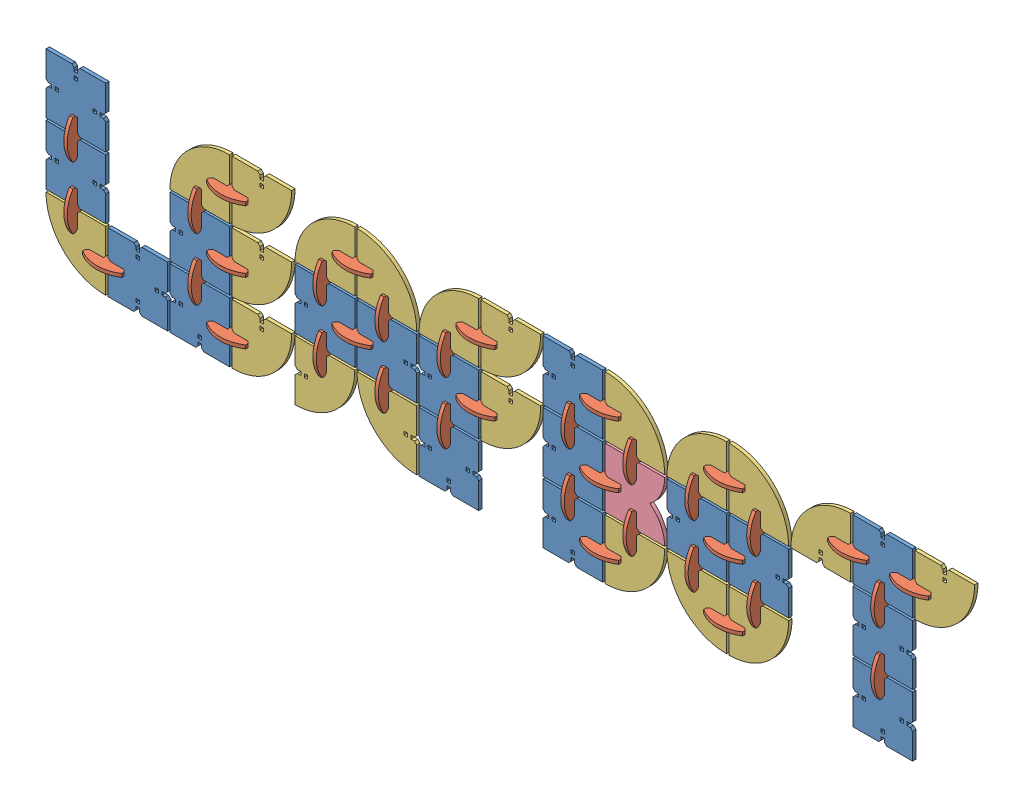
SolidWorks assembly Assem1, configuration Default. Lengths in mm.
Overall size (809 160 21).
74 component instances, 4 part files, 220 mates.
Components (placement in the parent):
- Part4-1: Part4 [Default] at (2.3941 27.4679 47.1684) size (52 52 3)
- Part6-1: Part6 [Default] at (-24.6059 25.9679 48.6684) x (1 0 0) z (0 1 0) size (34 21 3)
- Part4-2: Part4 [Default] at (-51.6059 81.4679 47.1684) size (52 52 3)
- Part5-1: Part5 [Default] at (-51.6059 27.4679 47.1684) x (-1 0 0) z (0 0 1) size (52 52 3)
- Part6-2: Part6 [Default] at (-53.1059 54.4679 48.6684) x (0 -1 0) z (1 0 0) size (34 21 3)
- Part6-3: Part6 [Default] at (-53.1059 108.4679 48.6684) x (0 1 0) z (1 0 0) size (34 21 3)
- Part4-3: Part4 [Default] at (-51.6059 135.4679 47.1684) size (52 52 3)
- Part4-4: Part4 [Default] at (56.3941 27.4679 47.1684) size (52 52 3)
- Part4-5: Part4 [Default] at (56.3941 81.4679 47.1684) size (52 52 3)
- Part6-4: Part6 [Default] at (57.8941 54.4679 48.6684) x (0 -1 0) z (-1 0 0) size (34 21 3)
- Part6-5: Part6 [Default] at (54.8941 108.4679 48.6684) x (0 1 0) z (1 0 0) size (34 21 3)
- Part5-2: Part5 [Default] at (56.3941 135.4679 47.1684) x (0 1 0) z (0 0 1) size (52 52 3)
- Part6-6: Part6 [Default] at (83.3941 28.9679 48.6684) x (1 0 0) z (0 -1 0) size (34 21 3)
- Part6-7: Part6 [Default] at (83.3941 82.9679 48.6684) x (1 0 0) z (0 -1 0) size (34 21 3)
- Part6-8: Part6 [Default] at (83.3941 136.9679 48.6684) x (1 0 0) z (0 -1 0) size (34 21 3)
- Part5-3: Part5 [Default] at (110.3941 135.4679 47.1684) x (0 -1 0) z (0 0 1) size (52 52 3)
- Part5-4: Part5 [Default] at (110.3941 81.4679 47.1684) x (0 -1 0) z (0 0 1) size (52 52 3)
- Part5-5: Part5 [Default] at (110.3941 27.4679 47.1684) x (0 -1 0) z (0 0 1) size (52 52 3)
- Part5-6: Part5 [Default] at (165.3941 27.4679 47.1684) x (0 -1 0) z (0 0 1) size (52 52 3)
- Part4-6: Part4 [Default] at (165.3941 81.4679 47.1684) size (52 52 3)
- Part6-9: Part6 [Default] at (163.8941 54.4679 48.6684) x (0 1 0) z (1 0 0) size (34 21 3)
- Part5-7: Part5 [Default] at (165.3941 135.4679 47.1684) x (0 1 0) z (0 0 1) size (52 52 3)
- Part6-10: Part6 [Default] at (163.8941 108.4679 48.6684) x (0 1 0) z (1 0 0) size (34 21 3)
- Part6-11: Part6 [Default] at (192.3941 136.9679 48.6684) x (1 0 0) z (0 -1 0) size (34 21 3)
- Part5-8: Part5 [Default] at (219.3941 135.4679 47.1684) size (52 52 3)
- Part6-12: Part6 [Default] at (220.8941 108.4679 48.6684) x (0 1 0) z (-1 0 0) size (34 21 3)
- Part4-7: Part4 [Default] at (219.3941 81.4679 47.1684) size (52 52 3)
- Part6-13: Part6 [Default] at (192.3941 82.9679 48.6684) x (1 0 0) z (0 -1 0) size (34 21 3)
- Part6-14: Part6 [Default] at (220.8941 54.4679 48.6684) x (0 1 0) z (-1 0 0) size (34 21 3)
- Part5-9: Part5 [Default] at (219.3941 27.4679 47.1684) x (-1 0 0) z (0 0 1) size (52 52 3)
- Part4-8: Part4 [Default] at (273.3941 27.4679 47.1684) size (52 52 3)
- Part6-15: Part6 [Default] at (271.8941 54.4679 48.6684) x (0 -1 0) z (1 0 0) size (34 21 3)
- Part4-9: Part4 [Default] at (273.3941 81.4679 47.1684) size (52 52 3)
- Part6-16: Part6 [Default] at (271.8941 108.4679 48.6684) x (0 1 0) z (1 0 0) size (34 21 3)
- Part5-10: Part5 [Default] at (273.3941 135.4679 47.1684) x (0 1 0) z (0 0 1) size (52 52 3)
- Part6-17: Part6 [Default] at (300.3941 82.9679 48.6684) x (1 0 0) z (0 -1 0) size (34 21 3)
- Part6-18: Part6 [Default] at (300.3941 136.9679 48.6684) x (1 0 0) z (0 -1 0) size (34 21 3)
- Part5-11: Part5 [Default] at (327.3941 135.4679 47.1684) x (0 -1 0) z (0 0 1) size (52 52 3)
- Part5-12: Part5 [Default] at (327.3941 81.4679 47.1684) x (0 -1 0) z (0 0 1) size (52 52 3)
- Part4-10: Part4 [Default] at (381.3941 27.4679 47.1684) size (52 52 3)
- Part6-19: Part6 [Default] at (379.8941 54.4679 48.6684) x (0 1 0) z (1 0 0) size (34 21 3)
- Part4-11: Part4 [Default] at (381.3941 81.4679 47.1684) size (52 52 3)
- Part4-12: Part4 [Default] at (381.3941 135.4679 47.1684) size (52 52 3)
- Part6-20: Part6 [Default] at (379.8941 108.4679 48.6684) x (0 1 0) z (1 0 0) size (34 21 3)
- Part6-21: Part6 [Default] at (408.3941 28.9679 48.6684) x (1 0 0) z (0 -1 0) size (34 21 3)
- Part6-22: Part6 [Default] at (408.3941 79.9679 48.6684) x (1 0 0) z (0 1 0) size (34 21 3)
- Part6-23: Part6 [Default] at (408.3941 133.9679 48.6684) x (1 0 0) z (0 1 0) size (34 21 3)
- Part5-13: Part5 [Default] at (435.3941 135.4679 47.1684) size (52 52 3)
- Part7-1: Part7 [Default] at (435.3941 81.4679 47.1684) size (52 52 3)
- Part5-14: Part5 [Default] at (435.3941 27.4679 47.1684) x (0 -1 0) z (0 0 1) size (52 52 3)
- Part6-24: Part6 [Default] at (436.8941 108.4679 48.6684) x (0 -1 0) z (-1 0 0) size (34 21 3)
- Part6-25: Part6 [Default] at (436.8941 54.4679 48.6684) x (0 -1 0) z (-1 0 0) size (34 21 3)
- Part5-15: Part5 [Default] at (489.3941 27.4679 47.1684) x (-1 0 0) z (0 0 1) size (52 52 3)
- Part6-26: Part6 [Default] at (490.8941 54.4679 48.6684) x (0 -1 0) z (-1 0 0) size (34 21 3)
- Part4-13: Part4 [Default] at (489.3941 81.4679 47.1684) size (52 52 3)
- Part6-27: Part6 [Default] at (490.8941 108.4679 48.6684) x (0 -1 0) z (-1 0 0) size (34 21 3)
- Part5-16: Part5 [Default] at (489.3941 135.4679 47.1684) x (0 1 0) z (0 0 1) size (52 52 3)
- Part6-28: Part6 [Default] at (516.3941 136.9679 48.6684) x (1 0 0) z (0 -1 0) size (34 21 3)
- Part6-29: Part6 [Default] at (516.3941 82.9679 48.6684) x (1 0 0) z (0 -1 0) size (34 21 3)
- Part6-30: Part6 [Default] at (516.3941 25.9679 48.6684) x (1 0 0) z (0 1 0) size (34 21 3)
- Part5-17: Part5 [Default] at (543.3941 135.4679 47.1684) size (52 52 3)
- Part4-14: Part4 [Default] at (543.3941 81.4679 47.1684) size (52 52 3)
- Part5-18: Part5 [Default] at (543.3941 27.4679 47.1684) x (0 -1 0) z (0 0 1) size (52 52 3)
- Part6-31: Part6 [Default] at (544.8941 108.4679 48.6684) x (0 -1 0) z (-1 0 0) size (34 21 3)
- Part6-32: Part6 [Default] at (544.8941 54.4679 48.6684) x (0 -1 0) z (-1 0 0) size (34 21 3)
- Part5-19: Part5 [Default] at (597.3941 135.4679 47.1684) x (0 1 0) z (0 0 1) size (52 52 3)
- Part6-33: Part6 [Default] at (624.3941 136.9679 48.6684) x (1 0 0) z (0 -1 0) size (34 21 3)
- Part4-15: Part4 [Default] at (651.3941 135.4679 47.1684) size (52 52 3)
- Part4-16: Part4 [Default] at (651.3941 81.4679 47.1684) size (52 52 3)
- Part4-17: Part4 [Default] at (651.3941 27.4679 47.1684) size (52 52 3)
- Part6-34: Part6 [Default] at (678.3941 136.9679 48.6684) x (1 0 0) z (0 -1 0) size (34 21 3)
- Part5-20: Part5 [Default] at (705.3941 135.4679 50.1684) x (1 0 0) z (0 0 -1) size (52 52 3)
- Part6-35: Part6 [Default] at (652.8941 108.4679 48.6684) x (0 -1 0) z (-1 0 0) size (34 21 3)
- Part6-36: Part6 [Default] at (652.8941 54.4679 48.6684) x (0 -1 0) z (-1 0 0) size (34 21 3)
Mates (geometry in assembly coordinates):
- Coincident5: coincident anti-aligned: plane of Part4-1 through (-21.6059 28.9679 50.1684) normal (0 -1 0); plane of Part6-1 through (-24.6059 28.9679 69.5684) normal (0 1 0)
- Coincident6: coincident anti-aligned: plane of Part4-1 through (2.3941 27.4679 47.1684) normal (0 0 -1); plane of Part6-1 through (-15.6059 28.9679 47.1684) normal (0 0 1)
- Coincident7: coincident anti-aligned: plane of Part4-1 through (-18.6059 27.4679 50.1684) normal (-1 0 0); plane of Part6-1 through (-18.6059 28.9679 47.1684) normal (1 0 0)
- Coincident8: coincident anti-aligned: plane of Part6-1 through (-24.6059 25.9679 69.5684) normal (0 -1 0); plane of Part5-1 through (-27.6059 25.9679 50.1684) normal (0 1 0)
- Coincident9: coincident aligned: plane of Part4-1 through (2.3941 27.4679 50.1684) normal (0 0 1); plane of Part5-1 through (-25.6059 53.4679 50.1684) normal (0 0 1)
- Coincident10: coincident anti-aligned: plane of Part6-1 through (-30.6059 28.9679 50.1684) normal (-1 0 0); plane of Part5-1 through (-30.6059 25.9679 50.1684) normal (1 0 0)
- Coincident12: coincident anti-aligned: plane of Part5-1 through (-50.1059 48.4679 50.1684) normal (0 1 0); plane of Part6-2 through (-50.1059 48.4679 47.1684) normal (0 -1 0)
- Coincident13: coincident anti-aligned: plane of Part5-1 through (-50.1059 51.4679 50.1684) normal (-1 0 0); plane of Part6-2 through (-50.1059 54.4679 69.5684) normal (1 0 0)
- Coincident14: coincident anti-aligned: plane of Part5-1 through (-25.6059 53.4679 47.1684) normal (0 0 -1); plane of Part6-2 through (-50.1059 45.4679 47.1684) normal (0 0 1)
- Coincident15: coincident anti-aligned: plane of Part4-2 through (-51.6059 60.4679 50.1684) normal (0 -1 0); plane of Part6-2 through (-50.1059 60.4679 50.1684) normal (0 1 0)
- Coincident16: coincident: plane of Part4-2 through (-51.6059 81.4679 47.1684) normal (0 0 -1); line of Part6-2 through (-50.1059 66.4679 47.1684) axis (0 1 0)
- Coincident17: coincident anti-aligned: plane of Part4-2 through (-53.1059 63.4679 50.1684) normal (1 0 0); plane of Part6-2 through (-53.1059 54.4679 69.5684) normal (-1 0 0)
- Coincident18: coincident anti-aligned: plane of Part4-2 through (-50.1059 105.4679 50.1684) normal (-1 0 0); plane of Part6-3 through (-50.1059 108.4679 27.7684) normal (1 0 0)
- Coincident19: coincident anti-aligned: plane of Part4-2 through (-51.6059 102.4679 50.1684) normal (0 1 0); plane of Part6-3 through (-50.1059 102.4679 47.1684) normal (0 -1 0)
- Coincident20: coincident anti-aligned: plane of Part4-2 through (-51.6059 81.4679 47.1684) normal (0 0 -1); plane of Part6-3 through (-50.1059 99.4679 47.1684) normal (0 0 1)
- Coincident21: coincident anti-aligned: plane of Part6-3 through (-50.1059 123.4679 50.1684) normal (0 0 -1); plane of Part4-3 through (-51.6059 135.4679 50.1684) normal (0 0 1)
- Coincident22: coincident anti-aligned: plane of Part6-3 through (-53.1059 108.4679 27.7684) normal (-1 0 0); plane of Part4-3 through (-53.1059 111.4679 50.1684) normal (1 0 0)
- Coincident23: coincident anti-aligned: plane of Part6-3 through (-50.1059 114.4679 50.1684) normal (0 1 0); plane of Part4-3 through (-51.6059 114.4679 50.1684) normal (0 -1 0)
- Coincident24: coincident aligned: plane of Part4-1 through (2.3941 27.4679 50.1684) normal (0 0 1); plane of Part4-4 through (56.3941 27.4679 50.1684) normal (0 0 1)
- Coincident25: coincident aligned: plane of Part4-1 through (5.8941 1.4679 50.1684) normal (0 -1 0); plane of Part4-4 through (30.3941 1.4679 50.1684) normal (0 -1 0)
- Distance1: distance = 2 mm anti-aligned: plane of Part4-4 through (30.3941 23.9679 50.1684) normal (-1 0 0); plane of Part4-1 through (28.3941 1.4679 50.1684) normal (1 0 0)
- Coincident27: coincident anti-aligned: plane of Part4-4 through (54.8941 48.4679 50.1684) normal (1 0 0); plane of Part6-4 through (54.8941 54.4679 27.7684) normal (-1 0 0)
- Coincident28: coincident anti-aligned: plane of Part4-4 through (56.3941 48.4679 50.1684) normal (0 1 0); plane of Part6-4 through (54.8941 48.4679 50.1684) normal (0 -1 0)
- Coincident29: coincident anti-aligned: plane of Part4-4 through (56.3941 27.4679 47.1684) normal (0 0 -1); plane of Part6-4 through (54.8941 45.4679 47.1684) normal (0 0 1)
- Coincident30: coincident anti-aligned: plane of Part4-5 through (56.3941 60.4679 50.1684) normal (0 -1 0); plane of Part6-4 through (54.8941 60.4679 47.1684) normal (0 1 0)
- Coincident31: coincident: plane of Part4-5 through (56.3941 81.4679 50.1684) normal (0 0 1); line of Part6-4 through (57.8941 66.4679 50.1684) axis (0 1 0)
- Coincident32: coincident anti-aligned: plane of Part4-5 through (57.8941 60.4679 50.1684) normal (-1 0 0); plane of Part6-4 through (57.8941 54.4679 27.7684) normal (1 0 0)
- Coincident33: coincident anti-aligned: plane of Part4-5 through (57.8941 105.4679 50.1684) normal (-1 0 0); plane of Part6-5 through (57.8941 108.4679 27.7684) normal (1 0 0)
- Coincident34: coincident anti-aligned: plane of Part4-5 through (56.3941 102.4679 50.1684) normal (0 1 0); plane of Part6-5 through (57.8941 102.4679 47.1684) normal (0 -1 0)
- Coincident35: coincident anti-aligned: plane of Part4-5 through (56.3941 81.4679 47.1684) normal (0 0 -1); plane of Part6-5 through (57.8941 93.4679 47.1684) normal (0 0 1)
- Coincident37: coincident anti-aligned: plane of Part6-5 through (57.8941 114.4679 50.1684) normal (0 1 0); plane of Part5-2 through (54.8941 114.4679 50.1684) normal (0 -1 0)
- Coincident38: coincident anti-aligned: plane of Part6-5 through (57.8941 108.4679 27.7684) normal (1 0 0); plane of Part5-2 through (57.8941 114.4679 50.1684) normal (-1 0 0)
- Coincident39: coincident: line of Part6-5 through (57.8941 120.4679 50.1684) axis (0 1 0); plane of Part5-2 through (82.3941 109.4679 50.1684) normal (0 0 1)
- Coincident40: coincident anti-aligned: plane of Part4-4 through (80.3941 25.9679 50.1684) normal (0 1 0); plane of Part6-6 through (83.3941 25.9679 27.7684) normal (0 -1 0)
- Coincident41: coincident anti-aligned: plane of Part4-4 through (77.3941 27.4679 50.1684) normal (1 0 0); plane of Part6-6 through (77.3941 25.9679 47.1684) normal (-1 0 0)
- Coincident42: coincident anti-aligned: plane of Part4-4 through (56.3941 27.4679 47.1684) normal (0 0 -1); plane of Part6-6 through (74.3941 25.9679 47.1684) normal (0 0 1)
- Coincident43: coincident anti-aligned: plane of Part4-5 through (80.3941 79.9679 50.1684) normal (0 1 0); plane of Part6-7 through (83.3941 79.9679 27.7684) normal (0 -1 0)
- Coincident44: coincident anti-aligned: plane of Part4-5 through (56.3941 81.4679 47.1684) normal (0 0 -1); plane of Part6-7 through (74.3941 79.9679 47.1684) normal (0 0 1)
- Coincident45: coincident anti-aligned: plane of Part4-5 through (77.3941 81.4679 50.1684) normal (1 0 0); plane of Part6-7 through (77.3941 79.9679 47.1684) normal (-1 0 0)
- Coincident46: coincident anti-aligned: plane of Part5-2 through (80.3941 133.9679 50.1684) normal (0 1 0); plane of Part6-8 through (83.3941 133.9679 27.7684) normal (0 -1 0)
- Coincident47: coincident anti-aligned: plane of Part5-2 through (77.3941 133.9679 50.1684) normal (1 0 0); plane of Part6-8 through (77.3941 133.9679 47.1684) normal (-1 0 0)
- Coincident48: coincident anti-aligned: plane of Part5-2 through (82.3941 109.4679 47.1684) normal (0 0 -1); plane of Part6-8 through (68.3941 133.9679 47.1684) normal (0 0 1)
- Coincident49: coincident anti-aligned: plane of Part6-8 through (89.3941 133.9679 50.1684) normal (1 0 0); plane of Part5-3 through (89.3941 136.9679 50.1684) normal (-1 0 0)
- Coincident50: coincident anti-aligned: plane of Part6-8 through (83.3941 133.9679 27.7684) normal (0 -1 0); plane of Part5-3 through (89.3941 133.9679 50.1684) normal (0 1 0)
- Coincident51: coincident anti-aligned: plane of Part6-8 through (92.3941 133.9679 50.1684) normal (0 0 -1); plane of Part5-3 through (84.3941 161.4679 50.1684) normal (0 0 1)
- Coincident52: coincident anti-aligned: plane of Part6-7 through (89.3941 79.9679 50.1684) normal (1 0 0); plane of Part5-4 through (89.3941 82.9679 50.1684) normal (-1 0 0)
- Coincident53: coincident anti-aligned: plane of Part6-7 through (92.3941 79.9679 50.1684) normal (0 0 -1); plane of Part5-4 through (84.3941 107.4679 50.1684) normal (0 0 1)
- Coincident54: coincident anti-aligned: plane of Part6-7 through (83.3941 82.9679 27.7684) normal (0 1 0); plane of Part5-4 through (86.3941 82.9679 50.1684) normal (0 -1 0)
- Coincident55: coincident anti-aligned: plane of Part6-6 through (89.3941 25.9679 50.1684) normal (1 0 0); plane of Part5-5 through (89.3941 28.9679 50.1684) normal (-1 0 0)
- Coincident56: coincident anti-aligned: plane of Part6-6 through (89.3941 25.9679 50.1684) normal (1 0 0); plane of Part5-5 through (89.3941 28.9679 50.1684) normal (-1 0 0)
- Coincident57: coincident anti-aligned: plane of Part6-6 through (98.3941 25.9679 50.1684) normal (0 0 -1); plane of Part5-5 through (84.3941 53.4679 50.1684) normal (0 0 1)
- Coincident58: coincident aligned: plane of Part5-5 through (84.3941 53.4679 50.1684) normal (0 0 1); plane of Part5-6 through (139.3941 53.4679 50.1684) normal (0 0 1)
- Distance2: distance = 165 mm anti-aligned: plane of Part5-6 through (139.3941 53.4679 50.1684) normal (-1 0 0); plane of Part5-1 through (-25.6059 1.4679 50.1684) normal (1 0 0)
- Coincident60: coincident aligned: plane of Part5-5 through (136.3941 53.4679 50.1684) normal (0 1 0); plane of Part5-6 through (191.3941 53.4679 50.1684) normal (0 1 0)
- Coincident61: coincident anti-aligned: plane of Part5-6 through (166.8941 51.4679 50.1684) normal (-1 0 0); plane of Part6-9 through (166.8941 54.4679 27.7684) normal (1 0 0)
- Coincident62: coincident anti-aligned: plane of Part5-6 through (166.8941 48.4679 50.1684) normal (0 1 0); plane of Part6-9 through (166.8941 48.4679 47.1684) normal (0 -1 0)
- Coincident63: coincident anti-aligned: plane of Part5-6 through (139.3941 53.4679 47.1684) normal (0 0 -1); plane of Part6-9 through (166.8941 45.4679 47.1684) normal (0 0 1)
- Coincident64: coincident anti-aligned: plane of Part4-6 through (165.3941 81.4679 50.1684) normal (0 0 1); plane of Part6-9 through (166.8941 63.4679 50.1684) normal (0 0 -1)
- Coincident66: coincident anti-aligned: plane of Part4-6 through (165.3941 60.4679 50.1684) normal (0 -1 0); plane of Part6-9 through (166.8941 60.4679 50.1684) normal (0 1 0)
- Coincident67: coincident anti-aligned: plane of Part4-6 through (166.8941 66.4679 50.1684) normal (-1 0 0); plane of Part6-9 through (166.8941 54.4679 27.7684) normal (1 0 0)
- Coincident69: coincident anti-aligned: plane of Part6-6 through (83.3941 28.9679 27.7684) normal (0 1 0); plane of Part5-5 through (86.3941 28.9679 50.1684) normal (0 -1 0)
- Coincident70: coincident anti-aligned: plane of Part4-6 through (166.8941 105.4679 50.1684) normal (-1 0 0); plane of Part6-10 through (166.8941 108.4679 27.7684) normal (1 0 0)
- Coincident71: coincident anti-aligned: plane of Part4-6 through (165.3941 102.4679 50.1684) normal (0 1 0); plane of Part6-10 through (166.8941 102.4679 47.1684) normal (0 -1 0)
- Coincident72: coincident anti-aligned: plane of Part4-6 through (165.3941 81.4679 50.1684) normal (0 0 1); plane of Part6-10 through (166.8941 99.4679 50.1684) normal (0 0 -1)
- Coincident73: coincident anti-aligned: plane of Part5-7 through (191.3941 109.4679 50.1684) normal (0 0 1); plane of Part6-10 through (166.8941 117.4679 50.1684) normal (0 0 -1)
- Coincident74: coincident anti-aligned: plane of Part5-7 through (163.8941 114.4679 50.1684) normal (0 -1 0); plane of Part6-10 through (166.8941 114.4679 50.1684) normal (0 1 0)
- Coincident75: coincident anti-aligned: plane of Part5-7 through (163.8941 111.4679 50.1684) normal (1 0 0); plane of Part6-10 through (163.8941 108.4679 27.7684) normal (-1 0 0)
- Coincident76: coincident anti-aligned: plane of Part5-7 through (189.3941 133.9679 50.1684) normal (0 1 0); plane of Part6-11 through (192.3941 133.9679 27.7684) normal (0 -1 0)
- Coincident77: coincident anti-aligned: plane of Part5-7 through (186.3941 133.9679 50.1684) normal (1 0 0); plane of Part6-11 through (186.3941 133.9679 47.1684) normal (-1 0 0)
- Coincident78: coincident anti-aligned: plane of Part5-7 through (191.3941 109.4679 47.1684) normal (0 0 -1); plane of Part6-11 through (183.3941 133.9679 47.1684) normal (0 0 1)
- Coincident79: coincident anti-aligned: plane of Part6-11 through (207.3941 133.9679 50.1684) normal (0 0 -1); plane of Part5-8 through (193.3941 109.4679 50.1684) normal (0 0 1)
- Coincident80: coincident anti-aligned: plane of Part6-11 through (198.3941 133.9679 50.1684) normal (1 0 0); plane of Part5-8 through (198.3941 136.9679 50.1684) normal (-1 0 0)
- Coincident81: coincident anti-aligned: plane of Part6-11 through (192.3941 136.9679 27.7684) normal (0 1 0); plane of Part5-8 through (195.3941 136.9679 50.1684) normal (0 -1 0)
- Coincident82: coincident anti-aligned: plane of Part5-8 through (217.8941 111.4679 50.1684) normal (1 0 0); plane of Part6-12 through (217.8941 108.4679 69.5684) normal (-1 0 0)
- Coincident83: coincident anti-aligned: plane of Part5-8 through (217.8941 114.4679 50.1684) normal (0 -1 0); plane of Part6-12 through (217.8941 114.4679 47.1684) normal (0 1 0)
- Coincident84: coincident anti-aligned: plane of Part5-8 through (193.3941 109.4679 47.1684) normal (0 0 -1); plane of Part6-12 through (217.8941 117.4679 47.1684) normal (0 0 1)
- Coincident85: coincident anti-aligned: plane of Part6-12 through (217.8941 102.4679 50.1684) normal (0 -1 0); plane of Part4-7 through (219.3941 102.4679 50.1684) normal (0 1 0)
- Coincident86: coincident anti-aligned: plane of Part6-12 through (217.8941 99.4679 50.1684) normal (0 0 -1); plane of Part4-7 through (219.3941 81.4679 50.1684) normal (0 0 1)
- Coincident87: coincident anti-aligned: plane of Part6-12 through (217.8941 108.4679 69.5684) normal (-1 0 0); plane of Part4-7 through (217.8941 102.4679 50.1684) normal (1 0 0)
- Coincident88: coincident anti-aligned: plane of Part4-6 through (189.3941 79.9679 50.1684) normal (0 1 0); plane of Part6-13 through (192.3941 79.9679 27.7684) normal (0 -1 0)
- Coincident89: coincident anti-aligned: plane of Part4-6 through (165.3941 81.4679 47.1684) normal (0 0 -1); plane of Part6-13 through (183.3941 79.9679 47.1684) normal (0 0 1)
- Coincident90: coincident anti-aligned: plane of Part4-6 through (186.3941 81.4679 50.1684) normal (1 0 0); plane of Part6-13 through (186.3941 79.9679 47.1684) normal (-1 0 0)
- Coincident91: coincident anti-aligned: plane of Part4-7 through (217.8941 57.4679 50.1684) normal (1 0 0); plane of Part6-14 through (217.8941 54.4679 69.5684) normal (-1 0 0)
- Coincident92: coincident anti-aligned: plane of Part4-7 through (219.3941 60.4679 50.1684) normal (0 -1 0); plane of Part6-14 through (217.8941 60.4679 47.1684) normal (0 1 0)
- Coincident93: coincident anti-aligned: plane of Part4-7 through (219.3941 81.4679 50.1684) normal (0 0 1); plane of Part6-14 through (217.8941 63.4679 50.1684) normal (0 0 -1)
- Coincident94: coincident anti-aligned: plane of Part6-14 through (217.8941 48.4679 50.1684) normal (0 -1 0); plane of Part5-9 through (220.8941 48.4679 50.1684) normal (0 1 0)
- Coincident95: coincident anti-aligned: plane of Part6-14 through (217.8941 45.4679 50.1684) normal (0 0 -1); plane of Part5-9 through (245.3941 53.4679 50.1684) normal (0 0 1)
- Coincident96: coincident anti-aligned: plane of Part6-14 through (217.8941 54.4679 69.5684) normal (-1 0 0); plane of Part5-9 through (217.8941 48.4679 50.1684) normal (1 0 0)
- Coincident97: coincident aligned: plane of Part5-9 through (245.3941 53.4679 50.1684) normal (0 0 1); plane of Part4-8 through (273.3941 27.4679 50.1684) normal (0 0 1)
- Coincident98: coincident aligned: plane of Part4-4 through (59.8941 1.4679 50.1684) normal (0 -1 0); plane of Part4-8 through (247.3941 1.4679 50.1684) normal (0 -1 0)
- Distance3: distance = 2 mm anti-aligned: plane of Part4-8 through (247.3941 23.9679 50.1684) normal (-1 0 0); plane of Part5-9 through (245.3941 1.4679 50.1684) normal (1 0 0)
- Coincident100: coincident anti-aligned: plane of Part4-8 through (273.3941 48.4679 50.1684) normal (0 1 0); plane of Part6-15 through (274.8941 48.4679 47.1684) normal (0 -1 0)
- Coincident101: coincident anti-aligned: plane of Part4-8 through (273.3941 27.4679 50.1684) normal (0 0 1); plane of Part6-15 through (274.8941 45.4679 50.1684) normal (0 0 -1)
- Coincident102: coincident anti-aligned: plane of Part4-8 through (274.8941 51.4679 50.1684) normal (-1 0 0); plane of Part6-15 through (274.8941 54.4679 69.5684) normal (1 0 0)
- Coincident103: coincident anti-aligned: plane of Part6-15 through (274.8941 69.4679 50.1684) normal (0 0 -1); plane of Part4-9 through (273.3941 81.4679 50.1684) normal (0 0 1)
- Coincident104: coincident anti-aligned: plane of Part6-15 through (271.8941 54.4679 69.5684) normal (-1 0 0); plane of Part4-9 through (271.8941 57.4679 50.1684) normal (1 0 0)
- Coincident105: coincident anti-aligned: plane of Part6-15 through (274.8941 60.4679 50.1684) normal (0 1 0); plane of Part4-9 through (273.3941 60.4679 50.1684) normal (0 -1 0)
- Coincident106: coincident anti-aligned: plane of Part4-9 through (274.8941 105.4679 50.1684) normal (-1 0 0); plane of Part6-16 through (274.8941 108.4679 27.7684) normal (1 0 0)
- Coincident107: coincident anti-aligned: plane of Part4-9 through (273.3941 102.4679 50.1684) normal (0 1 0); plane of Part6-16 through (274.8941 102.4679 47.1684) normal (0 -1 0)
- Coincident108: coincident anti-aligned: plane of Part4-9 through (273.3941 81.4679 47.1684) normal (0 0 -1); plane of Part6-16 through (274.8941 93.4679 47.1684) normal (0 0 1)
- Coincident109: coincident anti-aligned: plane of Part6-16 through (274.8941 117.4679 50.1684) normal (0 0 -1); plane of Part5-10 through (299.3941 109.4679 50.1684) normal (0 0 1)
- Coincident110: coincident anti-aligned: plane of Part6-16 through (274.8941 114.4679 50.1684) normal (0 1 0); plane of Part5-10 through (271.8941 114.4679 50.1684) normal (0 -1 0)
- Coincident111: coincident anti-aligned: plane of Part6-16 through (271.8941 108.4679 27.7684) normal (-1 0 0); plane of Part5-10 through (271.8941 111.4679 50.1684) normal (1 0 0)
- Coincident112: coincident anti-aligned: plane of Part4-9 through (297.3941 79.9679 50.1684) normal (0 1 0); plane of Part6-17 through (300.3941 79.9679 27.7684) normal (0 -1 0)
- Coincident113: coincident anti-aligned: plane of Part4-9 through (273.3941 81.4679 47.1684) normal (0 0 -1); plane of Part6-17 through (291.3941 79.9679 47.1684) normal (0 0 1)
- Coincident114: coincident anti-aligned: plane of Part4-9 through (294.3941 81.4679 50.1684) normal (1 0 0); plane of Part6-17 through (294.3941 79.9679 47.1684) normal (-1 0 0)
- Coincident115: coincident anti-aligned: plane of Part5-10 through (297.3941 133.9679 50.1684) normal (0 1 0); plane of Part6-18 through (300.3941 133.9679 27.7684) normal (0 -1 0)
- Coincident116: coincident anti-aligned: plane of Part5-10 through (299.3941 109.4679 47.1684) normal (0 0 -1); plane of Part6-18 through (291.3941 133.9679 47.1684) normal (0 0 1)
- Coincident117: coincident anti-aligned: plane of Part5-10 through (294.3941 133.9679 50.1684) normal (1 0 0); plane of Part6-18 through (294.3941 133.9679 47.1684) normal (-1 0 0)
- Coincident118: coincident anti-aligned: plane of Part6-18 through (306.3941 133.9679 50.1684) normal (1 0 0); plane of Part5-11 through (306.3941 136.9679 50.1684) normal (-1 0 0)
- Coincident119: coincident anti-aligned: plane of Part6-18 through (300.3941 133.9679 27.7684) normal (0 -1 0); plane of Part5-11 through (306.3941 133.9679 50.1684) normal (0 1 0)
- Coincident120: coincident anti-aligned: plane of Part6-18 through (309.3941 133.9679 50.1684) normal (0 0 -1); plane of Part5-11 through (301.3941 161.4679 50.1684) normal (0 0 1)
- Coincident121: coincident anti-aligned: plane of Part6-17 through (306.3941 79.9679 50.1684) normal (1 0 0); plane of Part5-12 through (306.3941 82.9679 50.1684) normal (-1 0 0)
- Coincident122: coincident anti-aligned: plane of Part6-17 through (315.3941 79.9679 50.1684) normal (0 0 -1); plane of Part5-12 through (301.3941 107.4679 50.1684) normal (0 0 1)
- Coincident123: coincident anti-aligned: plane of Part6-17 through (300.3941 82.9679 27.7684) normal (0 1 0); plane of Part5-12 through (303.3941 82.9679 50.1684) normal (0 -1 0)
- Coincident124: coincident aligned: plane of Part4-8 through (273.3941 27.4679 50.1684) normal (0 0 1); plane of Part4-10 through (381.3941 27.4679 50.1684) normal (0 0 1)
- Coincident125: coincident aligned: plane of Part4-8 through (276.8941 1.4679 50.1684) normal (0 -1 0); plane of Part4-10 through (355.3941 1.4679 50.1684) normal (0 -1 0)
- Distance4: distance = 2 mm: plane of Part4-10 through (355.3941 53.4679 50.1684) normal (-1 0 0); moEndPointRef_w of Part5-12
- Coincident127: coincident anti-aligned: plane of Part4-10 through (382.8941 51.4679 50.1684) normal (-1 0 0); plane of Part6-19 through (382.8941 54.4679 27.7684) normal (1 0 0)
- Coincident128: coincident anti-aligned: plane of Part4-10 through (381.3941 48.4679 50.1684) normal (0 1 0); plane of Part6-19 through (382.8941 48.4679 47.1684) normal (0 -1 0)
- Coincident129: coincident anti-aligned: plane of Part4-10 through (381.3941 27.4679 47.1684) normal (0 0 -1); plane of Part6-19 through (382.8941 45.4679 47.1684) normal (0 0 1)
- Coincident130: coincident aligned: plane of Part4-10 through (381.3941 27.4679 50.1684) normal (0 0 1); plane of Part4-11 through (381.3941 81.4679 50.1684) normal (0 0 1)
- Coincident131: coincident anti-aligned: plane of Part6-19 through (379.8941 54.4679 27.7684) normal (-1 0 0); plane of Part4-11 through (379.8941 57.4679 50.1684) normal (1 0 0)
- Coincident132: coincident anti-aligned: plane of Part6-19 through (382.8941 60.4679 50.1684) normal (0 1 0); plane of Part4-11 through (381.3941 60.4679 50.1684) normal (0 -1 0)
- Coincident133: coincident anti-aligned: plane of Part4-11 through (382.8941 105.4679 50.1684) normal (-1 0 0); plane of Part6-20 through (382.8941 108.4679 27.7684) normal (1 0 0)
- Coincident134: coincident anti-aligned: plane of Part4-11 through (381.3941 102.4679 50.1684) normal (0 1 0); plane of Part6-20 through (382.8941 102.4679 47.1684) normal (0 -1 0)
- Coincident135: coincident anti-aligned: plane of Part4-11 through (381.3941 81.4679 47.1684) normal (0 0 -1); plane of Part6-20 through (382.8941 99.4679 47.1684) normal (0 0 1)
- Coincident137: coincident anti-aligned: plane of Part4-12 through (381.3941 114.4679 50.1684) normal (0 -1 0); plane of Part6-20 through (382.8941 114.4679 50.1684) normal (0 1 0)
- Coincident138: coincident anti-aligned: plane of Part4-12 through (382.8941 114.4679 50.1684) normal (-1 0 0); plane of Part6-20 through (382.8941 108.4679 27.7684) normal (1 0 0)
- Coincident139: coincident anti-aligned: plane of Part4-12 through (381.3941 135.4679 47.1684) normal (0 0 -1); plane of Part6-20 through (382.8941 123.4679 47.1684) normal (0 0 1)
- Coincident140: coincident anti-aligned: plane of Part4-10 through (405.3941 25.9679 50.1684) normal (0 1 0); plane of Part6-21 through (408.3941 25.9679 27.7684) normal (0 -1 0)
- Coincident141: coincident anti-aligned: plane of Part4-10 through (402.3941 27.4679 50.1684) normal (1 0 0); plane of Part6-21 through (402.3941 25.9679 47.1684) normal (-1 0 0)
- Coincident142: coincident anti-aligned: plane of Part4-10 through (381.3941 27.4679 47.1684) normal (0 0 -1); plane of Part6-21 through (399.3941 25.9679 47.1684) normal (0 0 1)
- Coincident143: coincident anti-aligned: plane of Part4-11 through (405.3941 79.9679 50.1684) normal (0 1 0); plane of Part6-22 through (408.3941 79.9679 69.5684) normal (0 -1 0)
- Coincident144: coincident anti-aligned: plane of Part4-11 through (381.3941 81.4679 50.1684) normal (0 0 1); plane of Part6-22 through (393.3941 82.9679 50.1684) normal (0 0 -1)
- Coincident145: coincident anti-aligned: plane of Part4-11 through (402.3941 81.4679 50.1684) normal (1 0 0); plane of Part6-22 through (402.3941 82.9679 50.1684) normal (-1 0 0)
- Coincident146: coincident anti-aligned: plane of Part4-12 through (402.3941 136.9679 50.1684) normal (0 -1 0); plane of Part6-23 through (408.3941 136.9679 69.5684) normal (0 1 0)
- Coincident147: coincident anti-aligned: plane of Part4-12 through (381.3941 135.4679 47.1684) normal (0 0 -1); plane of Part6-23 through (399.3941 136.9679 47.1684) normal (0 0 1)
- Coincident148: coincident anti-aligned: plane of Part4-12 through (402.3941 135.4679 50.1684) normal (1 0 0); plane of Part6-23 through (402.3941 136.9679 50.1684) normal (-1 0 0)
- Coincident149: coincident aligned: plane of Part4-12 through (381.3941 135.4679 50.1684) normal (0 0 1); plane of Part5-13 through (409.3941 109.4679 50.1684) normal (0 0 1)
- Coincident150: coincident anti-aligned: plane of Part6-23 through (414.3941 136.9679 47.1684) normal (1 0 0); plane of Part5-13 through (414.3941 136.9679 50.1684) normal (-1 0 0)
- Coincident151: coincident anti-aligned: plane of Part6-23 through (408.3941 136.9679 69.5684) normal (0 1 0); plane of Part5-13 through (411.3941 136.9679 50.1684) normal (0 -1 0)
- Coincident152: coincident anti-aligned: plane of Part6-22 through (423.3941 82.9679 50.1684) normal (0 0 -1); plane of Part7-1 through (435.3941 81.4679 50.1684) normal (0 0 1)
- Coincident153: coincident anti-aligned: plane of Part6-22 through (414.3941 82.9679 47.1684) normal (1 0 0); plane of Part7-1 through (414.3941 81.4679 50.1684) normal (-1 0 0)
- Coincident154: coincident anti-aligned: plane of Part6-22 through (408.3941 79.9679 69.5684) normal (0 -1 0); plane of Part7-1 through (414.3941 79.9679 50.1684) normal (0 1 0)
- Coincident155: coincident anti-aligned: plane of Part6-21 through (414.3941 25.9679 50.1684) normal (1 0 0); plane of Part5-14 through (414.3941 28.9679 50.1684) normal (-1 0 0)
- Coincident156: coincident aligned: plane of Part4-10 through (381.3941 27.4679 50.1684) normal (0 0 1); plane of Part5-14 through (409.3941 53.4679 50.1684) normal (0 0 1)
- Coincident157: coincident anti-aligned: plane of Part6-21 through (408.3941 25.9679 27.7684) normal (0 -1 0); plane of Part5-14 through (414.3941 25.9679 50.1684) normal (0 1 0)
- Coincident158: coincident anti-aligned: plane of Part7-1 through (433.8941 102.4679 50.1684) normal (1 0 0); plane of Part6-24 through (433.8941 108.4679 27.7684) normal (-1 0 0)
- Coincident159: coincident anti-aligned: plane of Part7-1 through (435.3941 102.4679 50.1684) normal (0 1 0); plane of Part6-24 through (433.8941 102.4679 50.1684) normal (0 -1 0)
- Coincident160: coincident anti-aligned: plane of Part7-1 through (435.3941 81.4679 47.1684) normal (0 0 -1); plane of Part6-24 through (433.8941 93.4679 47.1684) normal (0 0 1)
- Coincident161: coincident anti-aligned: plane of Part5-14 through (433.8941 48.4679 50.1684) normal (1 0 0); plane of Part6-25 through (433.8941 54.4679 27.7684) normal (-1 0 0)
- Coincident162: coincident anti-aligned: plane of Part5-14 through (436.8941 48.4679 50.1684) normal (0 1 0); plane of Part6-25 through (433.8941 48.4679 50.1684) normal (0 -1 0)
- Coincident163: coincident anti-aligned: plane of Part5-14 through (409.3941 53.4679 47.1684) normal (0 0 -1); plane of Part6-25 through (433.8941 39.4679 47.1684) normal (0 0 1)
- Coincident164: coincident aligned: plane of Part5-14 through (461.3941 53.4679 50.1684) normal (0 1 0); plane of Part5-15 through (515.3941 53.4679 50.1684) normal (0 1 0)
- Coincident165: coincident aligned: plane of Part5-14 through (409.3941 53.4679 50.1684) normal (0 0 1); plane of Part5-15 through (515.3941 53.4679 50.1684) normal (0 0 1)
- Distance5: distance = 2 mm: unknown of Part5-15; unknown of Part5-14
- Coincident167: coincident anti-aligned: plane of Part5-15 through (487.8941 48.4679 50.1684) normal (1 0 0); plane of Part6-26 through (487.8941 54.4679 27.7684) normal (-1 0 0)
- Coincident168: coincident anti-aligned: plane of Part5-15 through (490.8941 48.4679 50.1684) normal (0 1 0); plane of Part6-26 through (487.8941 48.4679 50.1684) normal (0 -1 0)
- Coincident169: coincident anti-aligned: plane of Part5-15 through (515.3941 53.4679 47.1684) normal (0 0 -1); plane of Part6-26 through (487.8941 45.4679 47.1684) normal (0 0 1)
- Coincident170: coincident aligned: plane of Part5-15 through (515.3941 53.4679 50.1684) normal (0 0 1); plane of Part4-13 through (489.3941 81.4679 50.1684) normal (0 0 1)
- Coincident171: coincident anti-aligned: plane of Part6-26 through (487.8941 60.4679 47.1684) normal (0 1 0); plane of Part4-13 through (489.3941 60.4679 50.1684) normal (0 -1 0)
- Coincident172: coincident anti-aligned: plane of Part6-26 through (487.8941 54.4679 27.7684) normal (-1 0 0); plane of Part4-13 through (487.8941 63.4679 50.1684) normal (1 0 0)
- Coincident173: coincident anti-aligned: plane of Part4-13 through (487.8941 102.4679 50.1684) normal (1 0 0); plane of Part6-27 through (487.8941 108.4679 27.7684) normal (-1 0 0)
- Coincident174: coincident anti-aligned: plane of Part4-13 through (489.3941 102.4679 50.1684) normal (0 1 0); plane of Part6-27 through (487.8941 102.4679 50.1684) normal (0 -1 0)
- Coincident175: coincident anti-aligned: plane of Part4-13 through (489.3941 81.4679 47.1684) normal (0 0 -1); plane of Part6-27 through (487.8941 93.4679 47.1684) normal (0 0 1)
- Coincident177: coincident anti-aligned: plane of Part6-27 through (487.8941 114.4679 47.1684) normal (0 1 0); plane of Part5-16 through (487.8941 114.4679 50.1684) normal (0 -1 0)
- Coincident178: coincident aligned: plane of Part4-13 through (489.3941 81.4679 50.1684) normal (0 0 1); plane of Part5-16 through (515.3941 109.4679 50.1684) normal (0 0 1)
- Coincident179: coincident anti-aligned: plane of Part6-27 through (490.8941 108.4679 27.7684) normal (1 0 0); plane of Part5-16 through (490.8941 114.4679 50.1684) normal (-1 0 0)
- Coincident180: coincident anti-aligned: plane of Part5-16 through (513.3941 133.9679 50.1684) normal (0 1 0); plane of Part6-28 through (516.3941 133.9679 27.7684) normal (0 -1 0)
- Coincident181: coincident anti-aligned: plane of Part5-16 through (510.3941 133.9679 50.1684) normal (1 0 0); plane of Part6-28 through (510.3941 133.9679 47.1684) normal (-1 0 0)
- Coincident182: coincident anti-aligned: plane of Part5-16 through (515.3941 109.4679 47.1684) normal (0 0 -1); plane of Part6-28 through (507.3941 133.9679 47.1684) normal (0 0 1)
- Coincident183: coincident anti-aligned: plane of Part4-13 through (513.3941 79.9679 50.1684) normal (0 1 0); plane of Part6-29 through (516.3941 79.9679 27.7684) normal (0 -1 0)
- Coincident184: coincident anti-aligned: plane of Part4-13 through (489.3941 81.4679 47.1684) normal (0 0 -1); plane of Part6-29 through (501.3941 79.9679 47.1684) normal (0 0 1)
- Coincident185: coincident anti-aligned: plane of Part4-13 through (510.3941 81.4679 50.1684) normal (1 0 0); plane of Part6-29 through (510.3941 79.9679 47.1684) normal (-1 0 0)
- Coincident186: coincident anti-aligned: plane of Part5-15 through (510.3941 28.9679 50.1684) normal (0 -1 0); plane of Part6-30 through (516.3941 28.9679 69.5684) normal (0 1 0)
- Coincident187: coincident anti-aligned: plane of Part5-15 through (515.3941 53.4679 47.1684) normal (0 0 -1); plane of Part6-30 through (507.3941 28.9679 47.1684) normal (0 0 1)
- Coincident188: coincident anti-aligned: plane of Part5-15 through (510.3941 25.9679 50.1684) normal (1 0 0); plane of Part6-30 through (510.3941 28.9679 50.1684) normal (-1 0 0)
- Coincident189: coincident aligned: plane of Part5-16 through (515.3941 109.4679 50.1684) normal (0 0 1); plane of Part5-17 through (517.3941 109.4679 50.1684) normal (0 0 1)
- Coincident190: coincident anti-aligned: plane of Part6-28 through (522.3941 133.9679 50.1684) normal (1 0 0); plane of Part5-17 through (522.3941 136.9679 50.1684) normal (-1 0 0)
- Coincident191: coincident anti-aligned: plane of Part6-28 through (516.3941 133.9679 27.7684) normal (0 -1 0); plane of Part5-17 through (522.3941 133.9679 50.1684) normal (0 1 0)
- Coincident192: coincident aligned: plane of Part5-17 through (517.3941 109.4679 50.1684) normal (0 0 1); plane of Part4-14 through (543.3941 81.4679 50.1684) normal (0 0 1)
- Coincident193: coincident aligned: plane of Part4-13 through (515.3941 107.4679 50.1684) normal (0 1 0); plane of Part4-14 through (539.8941 107.4679 50.1684) normal (0 1 0)
- Coincident194: coincident aligned: plane of Part5-17 through (517.3941 161.4679 50.1684) normal (-1 0 0); plane of Part4-14 through (517.3941 107.4679 50.1684) normal (-1 0 0)
- Coincident195: coincident aligned: plane of Part5-15 through (515.3941 53.4679 50.1684) normal (0 1 0); plane of Part5-18 through (569.3941 53.4679 50.1684) normal (0 1 0)
- Coincident196: coincident aligned: plane of Part4-14 through (517.3941 77.9679 50.1684) normal (-1 0 0); plane of Part5-18 through (517.3941 53.4679 50.1684) normal (-1 0 0)
- Coincident197: coincident aligned: plane of Part4-14 through (543.3941 81.4679 50.1684) normal (0 0 1); plane of Part5-18 through (517.3941 53.4679 50.1684) normal (0 0 1)
- Coincident198: coincident anti-aligned: plane of Part5-17 through (541.8941 111.4679 50.1684) normal (1 0 0); plane of Part6-31 through (541.8941 108.4679 27.7684) normal (-1 0 0)
- Coincident199: coincident anti-aligned: plane of Part4-14 through (543.3941 102.4679 50.1684) normal (0 1 0); plane of Part6-31 through (541.8941 102.4679 50.1684) normal (0 -1 0)
- Coincident200: coincident anti-aligned: plane of Part5-17 through (517.3941 109.4679 47.1684) normal (0 0 -1); plane of Part6-31 through (541.8941 123.4679 47.1684) normal (0 0 1)
- Coincident201: coincident anti-aligned: plane of Part4-14 through (541.8941 57.4679 50.1684) normal (1 0 0); plane of Part6-32 through (541.8941 54.4679 27.7684) normal (-1 0 0)
- Coincident202: coincident anti-aligned: plane of Part5-18 through (544.8941 48.4679 50.1684) normal (0 1 0); plane of Part6-32 through (541.8941 48.4679 50.1684) normal (0 -1 0)
- Coincident203: coincident anti-aligned: plane of Part4-14 through (543.3941 81.4679 47.1684) normal (0 0 -1); plane of Part6-32 through (541.8941 63.4679 47.1684) normal (0 0 1)
- Coincident204: coincident aligned: plane of Part5-17 through (517.3941 109.4679 50.1684) normal (0 0 1); plane of Part5-19 through (623.3941 109.4679 50.1684) normal (0 0 1)
- Coincident205: coincident aligned: plane of Part5-17 through (517.3941 109.4679 50.1684) normal (0 -1 0); plane of Part5-19 through (571.3941 109.4679 50.1684) normal (0 -1 0)
- Distance6: distance = 2 mm: line of Part5-19 through (571.3941 109.4679 50.1684) axis (0 0 -1); plane of Part4-14 through (569.3941 84.9679 50.1684) normal (1 0 0)
- Coincident207: coincident anti-aligned: plane of Part5-19 through (621.3941 133.9679 50.1684) normal (0 1 0); plane of Part6-33 through (624.3941 133.9679 27.7684) normal (0 -1 0)
- Coincident208: coincident anti-aligned: plane of Part5-19 through (618.3941 133.9679 50.1684) normal (1 0 0); plane of Part6-33 through (618.3941 133.9679 47.1684) normal (-1 0 0)
- Coincident209: coincident anti-aligned: plane of Part5-19 through (623.3941 109.4679 47.1684) normal (0 0 -1); plane of Part6-33 through (615.3941 133.9679 47.1684) normal (0 0 1)
- Coincident210: coincident aligned: plane of Part5-19 through (623.3941 109.4679 50.1684) normal (0 0 1); plane of Part4-15 through (651.3941 135.4679 50.1684) normal (0 0 1)
- Coincident211: coincident aligned: plane of Part5-19 through (571.3941 109.4679 50.1684) normal (0 -1 0); plane of Part4-15 through (625.3941 109.4679 50.1684) normal (0 -1 0)
- Coincident212: coincident anti-aligned: plane of Part6-33 through (630.3941 133.9679 50.1684) normal (1 0 0); plane of Part4-15 through (630.3941 135.4679 50.1684) normal (-1 0 0)
- Coincident213: coincident aligned: plane of Part4-15 through (651.3941 135.4679 50.1684) normal (0 0 1); plane of Part4-16 through (651.3941 81.4679 50.1684) normal (0 0 1)
- Coincident214: coincident aligned: plane of Part4-15 through (677.3941 109.4679 50.1684) normal (1 0 0); plane of Part4-16 through (677.3941 84.9679 50.1684) normal (1 0 0)
- Coincident215: coincident aligned: plane of Part4-14 through (569.3941 107.4679 50.1684) normal (0 1 0); plane of Part4-16 through (677.3941 107.4679 50.1684) normal (0 1 0)
- Coincident216: coincident aligned: plane of Part4-16 through (651.3941 81.4679 50.1684) normal (0 0 1); plane of Part4-17 through (651.3941 27.4679 50.1684) normal (0 0 1)
- Coincident217: coincident aligned: plane of Part5-18 through (569.3941 53.4679 50.1684) normal (0 1 0); plane of Part4-17 through (677.3941 53.4679 50.1684) normal (0 1 0)
- Coincident218: coincident aligned: plane of Part4-16 through (677.3941 55.4679 50.1684) normal (1 0 0); plane of Part4-17 through (677.3941 30.9679 50.1684) normal (1 0 0)
- Coincident219: coincident anti-aligned: plane of Part4-15 through (675.3941 133.9679 50.1684) normal (0 1 0); plane of Part6-34 through (678.3941 133.9679 27.7684) normal (0 -1 0)
- Coincident220: coincident anti-aligned: plane of Part4-15 through (672.3941 135.4679 50.1684) normal (1 0 0); plane of Part6-34 through (672.3941 133.9679 47.1684) normal (-1 0 0)
- Coincident221: coincident anti-aligned: plane of Part4-15 through (651.3941 135.4679 47.1684) normal (0 0 -1); plane of Part6-34 through (669.3941 133.9679 47.1684) normal (0 0 1)
- Coincident222: coincident aligned: plane of Part4-15 through (677.3941 161.4679 50.1684) normal (0 1 0); plane of Part5-20 through (679.3941 161.4679 47.1684) normal (0 1 0)
- Coincident223: coincident anti-aligned: plane of Part6-34 through (684.3941 133.9679 50.1684) normal (1 0 0); plane of Part5-20 through (684.3941 133.9679 47.1684) normal (-1 0 0)
- Coincident224: coincident aligned: plane of Part4-15 through (651.3941 135.4679 50.1684) normal (0 0 1); plane of Part5-20 through (679.3941 161.4679 50.1684) normal (0 0 1)
- Coincident225: coincident anti-aligned: plane of Part4-16 through (649.8941 102.4679 50.1684) normal (1 0 0); plane of Part6-35 through (649.8941 108.4679 27.7684) normal (-1 0 0)
- Coincident226: coincident anti-aligned: plane of Part4-16 through (651.3941 102.4679 50.1684) normal (0 1 0); plane of Part6-35 through (649.8941 102.4679 50.1684) normal (0 -1 0)
- Coincident227: coincident anti-aligned: plane of Part4-16 through (651.3941 81.4679 47.1684) normal (0 0 -1); plane of Part6-35 through (649.8941 117.4679 47.1684) normal (0 0 1)
- Coincident228: coincident anti-aligned: plane of Part4-17 through (649.8941 48.4679 50.1684) normal (1 0 0); plane of Part6-36 through (649.8941 54.4679 27.7684) normal (-1 0 0)
- Coincident229: coincident anti-aligned: plane of Part4-17 through (651.3941 48.4679 50.1684) normal (0 1 0); plane of Part6-36 through (649.8941 48.4679 50.1684) normal (0 -1 0)
- Coincident230: coincident anti-aligned: plane of Part4-17 through (651.3941 27.4679 47.1684) normal (0 0 -1); plane of Part6-36 through (649.8941 45.4679 47.1684) normal (0 0 1)
